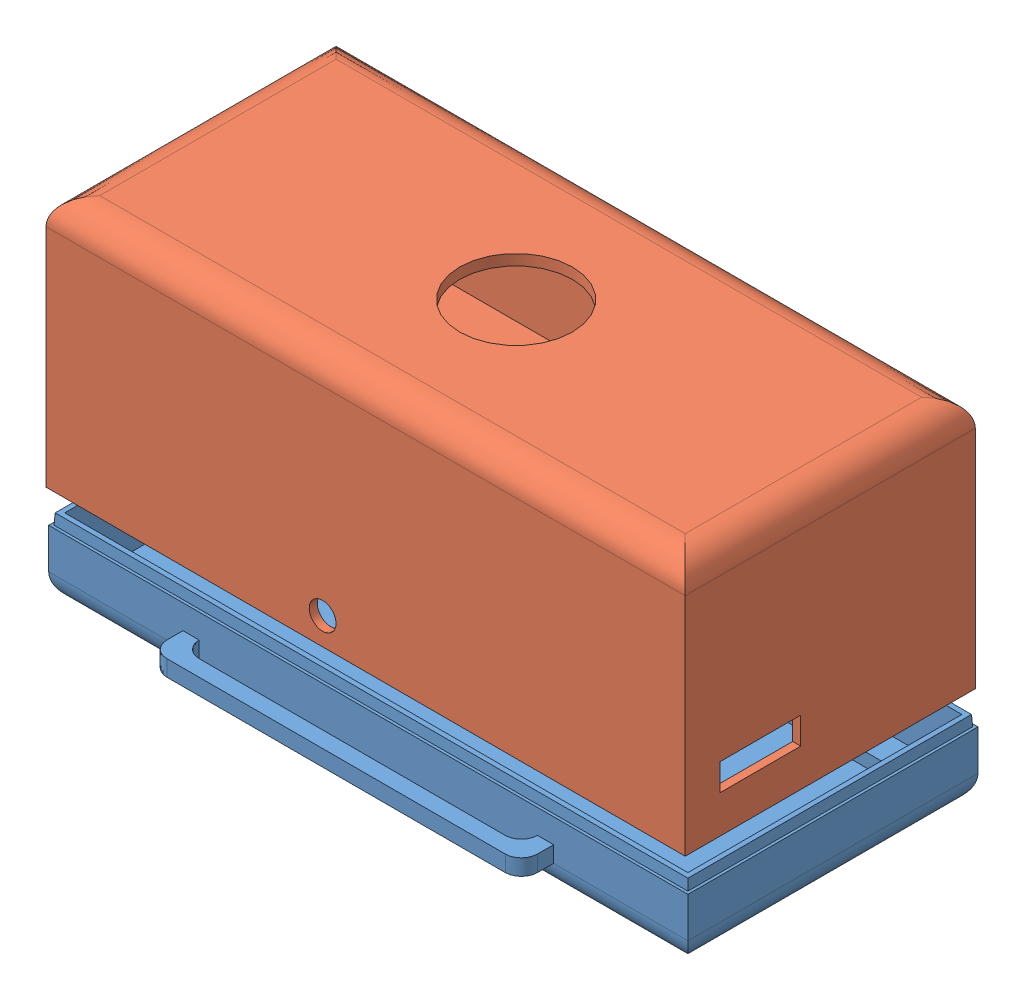
SolidWorks assembly Assieme1, configuration Default. Lengths in mm.
Overall size (119.48 65.41 66).
2 component instances, 2 part files, 0 mates.
Components (placement in the parent):
- Case-BOTTOM-1: Case-BOTTOM [Default] at (16.7242 52.3519 101.7857) size (119 14.5 66)
- Case-TOP-1: Case-TOP [Default] at (16.241 58.2617 101.8018) size (119 47 54)
